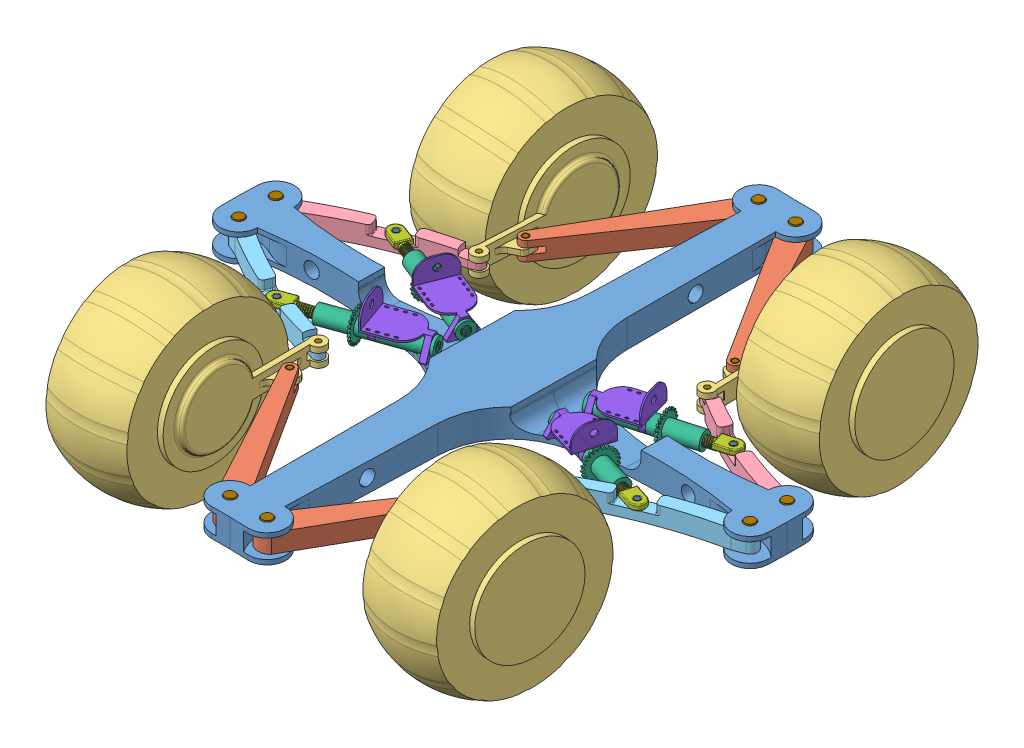
SolidWorks assembly Assembly, configuration Default. Lengths in mm.
Overall size (299.96 98.94 301.96).
45 component instances, 10 part files, 100 mates.
Components (placement in the parent):
- arm new_-1: arm new_ [Default] at (191.3072 172.5892 191.9509) size (299.96 15 300.6)
- arm1-1: arm1 [Default] at (104.0138 167.5892 118.0667) x (0.504061 0 0.863668) z (-0.863668 0 0.504061) size (99.65 10 13.4)
- arm1-2: arm1 [Default] at (58.7662 167.5892 117.3281) x (-0.533042 0 0.846089) z (-0.846089 0 -0.533042) size (99.65 10 13.4)
- arm1-6: arm1 [Default] at (55.0045 177.5892 356.5474) x (-0.50817 0 -0.861257) z (-0.861257 0 0.50817) size (99.65 10 13.4)
- arm1-9: arm1 [Default] at (100.1536 167.5892 357.105) x (0.524834 0 -0.851205) z (0.851205 0 0.524834) size (99.65 10 13.4)
- wheel2-1: wheel2 [Default] at (169.1966 172.6392 141.5765) x (0.999592 0 -0.02857) z (0.02857 0 0.999592) size (79.29 98.57 106.84)
- wheel2-2: wheel2 [Default] at (-7.5959 172.6392 138.9789) x (-0.998723 0 -0.050514) z (-0.050514 0 0.998723) size (79.29 98.57 106.84)
- wheel2-4: wheel2 [Default] at (-10.9833 172.6392 332.7058) x (-0.999915 0 0.013017) z (-0.013017 0 -0.999915) size (79.29 98.57 106.84)
- wheel2-6: wheel2 [Default] at (164.8246 172.6392 336.0802) x (0.996582 0 0.082612) z (0.082612 0 -0.996582) size (79.29 98.57 106.84)
- arm 2 new-1: arm 2 new [Default] at (204.9288 172.5892 223.1767) x (-0.915195 0 -0.403012) z (-0.403012 0 0.915195) size (91 10 10.53)
- arm 2 new-2: arm 2 new [Default] at (-45.319 172.5892 219.268) x (0.926876 0 -0.375368) z (-0.375368 0 -0.926876) size (91 10 10.53)
- arm inverted-1: arm inverted [Default] at (137.6621 167.5892 275.5223) x (0 1 0) z (0.928236 0 -0.371992) size (10 10.53 91)
- arm inverted-2: arm inverted [Default] at (15.309 167.5892 285.0263) x (0 1 0) z (-0.91443 0 -0.404745) size (10 10.53 91)
- pin3new-1: pin3new [Default] at (112.7999 172.5892 230.1102) x (0.109281 -0.915302 0.387659) z (0.248344 0.402768 0.880967) size (16.9 51.81 16.9)
- pin1new-1: pin1new [Default] at (135.513 172.5892 223.7074) x (0 1 0) z (0.271325 0 0.962488) size (5.63 60.02 8)
- pin1new-2: pin1new [Default] at (20.79 172.5892 219.062) x (0 1 0) z (0.369717 0 -0.929144) size (5.63 60.02 8)
- pin1new-4: pin1new [Default] at (19.9082 172.5892 253.6636) x (0 1 0) z (-0.336447 0 -0.941702) size (5.63 60.02 8)
- pin1new-6: pin1new [Default] at (135.3649 172.5892 252.5493) x (0 1 0) z (-0.295537 0 0.955331) size (5.63 60.02 8)
- ring-1: ring [Default] at (115.6874 172.5892 229.2962) x (0 -1 0) z (0.271325 0 0.962488) size (24.27 27.27 20.01)
- ring-2: ring [Default] at (115.4217 172.5892 246.3798) x (0 -1 0) z (-0.295537 0 0.955331) size (24.27 27.27 20.01)
- ring-4: ring [Default] at (43.6955 172.5892 228.1763) x (0 -1 0) z (0.369717 0 -0.929144) size (24.27 27.27 20.01)
- ring-6: ring [Default] at (43.4298 172.5892 245.2599) x (0 -1 0) z (-0.336447 0 -0.941702) size (24.27 27.27 20.01)
- pin3new-2: pin3new [Default] at (112.5557 172.5892 245.4931) x (0.053458 0.983504 -0.172805) z (0.290662 -0.180885 -0.939572) size (16.9 51.81 16.9)
- pin3new-4: pin3new [Default] at (46.483 172.5892 229.2855) x (0.117022 -0.948586 -0.294091) z (0.350709 0.316519 -0.881374) size (16.9 51.81 16.9)
- pin3new-6: pin3new [Default] at (46.2549 172.5892 244.2506) x (-0.303145 -0.433779 -0.848492) z (-0.145944 0.901019 -0.40849) size (16.9 51.81 16.9)
- parallel pin hardened_iso-3: parallel pin hardened_iso [ISO 8734 - 6 x 16 - A - St] at (67.2256 180.5892 377.2599) x (0 -1 0) z (-0.466512 0 0.884515) size (16 6 6)
- parallel pin hardened_iso-4: parallel pin hardened_iso [ISO 8734 - 6 x 16 - A - St] at (87.5318 180.5892 377.5758) x (0 -1 0) z (-0.291462 0 0.956582) size (16 6 6)
- parallel pin hardened_iso-6: parallel pin hardened_iso [ISO 8734 - 6 x 16 - A - St] at (219.2343 180.5892 249.2952) x (0 -1 0) z (-0.078395 0 0.996922) size (16 6 6)
- parallel pin hardened_iso-8: parallel pin hardened_iso [ISO 8734 - 6 x 16 - A - St] at (219.5405 180.5892 229.611) x (0 -1 0) z (0.157499 0 0.987519) size (16 6 6)
- parallel pin hardened_iso-10: parallel pin hardened_iso [ISO 8734 - 6 x 16 - A - St] at (91.8916 180.5892 97.2962) x (0 -1 0) z (0.388757 0 0.92134) size (16 6 6)
- parallel pin hardened_iso-12: parallel pin hardened_iso [ISO 8734 - 6 x 16 - A - St] at (71.5854 180.5892 96.9803) x (0 -1 0) z (0.585753 0 0.810489) size (16 6 6)
- parallel pin hardened_iso-14: parallel pin hardened_iso [ISO 8734 - 6 x 16 - A - St] at (-60.1171 180.5892 225.2609) x (0 -1 0) z (0.730525 0 0.682886) size (16 6 6)
- parallel pin hardened_iso-16: parallel pin hardened_iso [ISO 8734 - 6 x 16 - A - St] at (-60.4233 180.4892 244.9451) x (0 -1 0) z (0.82204 0 0.56943) size (16 6 6)
- groove pin 03_iso-2: groove pin 03_iso [ISO 8741-M3x8-St] at (-17.7449 171.9911 267.1161) x (0 1 0) z (-0.995304 0 0.096799) size (8 3 3)
- groove pin 03_iso-3: groove pin 03_iso [ISO 8741-M3x8-St] at (-16.3609 171.9911 204.2792) x (0 1 0) z (0.188455 0 0.982082) size (8 3 3)
- groove pin 03_iso-5: groove pin 03_iso [ISO 8741-M3x8-St] at (173.9972 171.9911 212.8587) x (0 1 0) z (0.395734 0 0.918365) size (8 3 3)
- groove pin 03_iso-7: groove pin 03_iso [ISO 8741-M3x8-St] at (173.563 171.9911 264.3661) x (0 1 0) z (0.6 0 0.8) size (8 3 3)
- parallel pin hardened_iso-19: parallel pin hardened_iso [ISO 8734 - 3 x 10 - A - St] at (141.2624 177.6392 280.5425) x (0 -1 0) z (0 0 1) size (10 3 3)
- parallel pin hardened_iso-20: parallel pin hardened_iso [ISO 8734 - 3 x 10 - A - St] at (142.6641 177.6392 195.758) x (0 -1 0) z (0.837169 0 0.546944) size (10 3 3)
- parallel pin hardened_iso-22: parallel pin hardened_iso [ISO 8734 - 3 x 10 - A - St] at (17.7405 177.6392 193.73) x (0 -1 0) z (0.395734 0 0.918365) size (10 3 3)
- parallel pin hardened_iso-24: parallel pin hardened_iso [ISO 8734 - 3 x 10 - A - St] at (16.3888 177.6392 278.9436) x (0 -1 0) z (0.837169 0 0.546944) size (10 3 3)
- parallel pin hardened_iso-26: parallel pin hardened_iso [ISO 8734 - 3 x 10 - A - St] at (135.2917 177.5892 300.1161) x (0 -1 0) z (0.837169 0 0.546944) size (10 3 3)
- parallel pin hardened_iso-28: parallel pin hardened_iso [ISO 8734 - 3 x 10 - A - St] at (20.9822 177.5892 298.8855) x (0 -1 0) z (0.837169 0 0.546944) size (10 3 3)
- parallel pin hardened_iso-30: parallel pin hardened_iso [ISO 8734 - 3 x 10 - A - St] at (23.0786 177.5892 173.9744) x (0 -1 0) z (0.6 0 0.8) size (10 3 3)
- parallel pin hardened_iso-32: parallel pin hardened_iso [ISO 8734 - 3 x 10 - A - St] at (137.7611 177.5892 175.89) x (0 -1 0) z (0.773678 0 0.63358) size (10 3 3)
Mates (geometry in assembly coordinates):
- Concentric1: concentric aligned: cylinder of arm new_-1 through (91.8916 180.0892 97.2962) axis (0 -1 0) radius 3; cylinder of arm1-1 through (91.8916 177.5892 97.2962) axis (0 -1 0) radius 3
- Coincident1: coincident anti-aligned: plane of arm new_-1 through (105.3916 177.5892 99.2962) normal (0 -1 0); plane of arm1-1 through (92.5799 177.5892 98.4756) normal (0 1 0)
- Concentric2: concentric aligned: cylinder of arm new_-1 through (71.5854 180.0892 96.9803) axis (0 -1 0) radius 3; cylinder of arm1-2 through (71.5854 177.5892 96.9803) axis (0 -1 0) radius 3
- Coincident2: coincident anti-aligned: plane of arm new_-1 through (58.0297 177.5892 98.5595) normal (0 -1 0); plane of arm1-2 through (70.8575 177.5892 98.1357) normal (0 1 0)
- Concentric5: concentric aligned: circle of arm new_-1; cylinder of arm1-6 through (67.2256 167.5892 377.2599) axis (0 1 0) radius 3
- Concentric7: concentric aligned: cylinder of arm new_-1 through (87.5318 180.0892 377.5758) axis (0 -1 0) radius 3; cylinder of arm1-9 through (87.5318 177.5892 377.5758) axis (0 -1 0) radius 3
- Coincident4: coincident anti-aligned: plane of arm new_-1 through (101.0875 177.5892 375.9966) normal (0 -1 0); plane of arm1-9 through (88.2485 177.5892 376.4134) normal (0 1 0)
- Coincident5: coincident anti-aligned: plane of arm new_-1 through (53.7256 177.5892 375.2599) normal (0 -1 0); plane of arm1-6 through (66.5317 177.5892 376.0838) normal (0 1 0)
- Concentric8: concentric aligned: cylinder of arm1-1 through (137.7611 177.5892 175.89) axis (0 -1 0) radius 1.75; cylinder of wheel2-1 through (137.7611 174.1392 175.89) axis (0 -1 0) radius 1.75
- Coincident6: coincident anti-aligned: plane of arm1-1 through (137.7611 174.1392 175.89) normal (0 -1 0); plane of wheel2-1 through (137.3224 174.1392 177.6712) normal (0 1 0)
- Concentric9: concentric anti-aligned: cylinder of arm1-2 through (23.0786 177.5892 173.9744) axis (0 -1 0) radius 1.75; cylinder of wheel2-2 through (23.0786 171.1392 173.9744) axis (0 1 0) radius 1.75
- Concentric10: concentric anti-aligned: cylinder of arm1-6 through (20.9822 167.5892 298.8855) axis (0 1 0) radius 1.75; cylinder of wheel2-4 through (20.9822 174.1392 298.8855) axis (0 -1 0) radius 1.75
- Coincident8: coincident anti-aligned: plane of arm1-6 through (27.8722 174.1392 294.8202) normal (0 -1 0); plane of wheel2-4 through (21.4485 174.1392 297.1114) normal (0 1 0)
- Concentric11: concentric anti-aligned: cylinder of arm1-9 through (135.2917 177.5892 300.1161) axis (0 -1 0) radius 1.75; cylinder of wheel2-6 through (135.2917 171.1392 300.1161) axis (0 1 0) radius 1.75
- Concentric12: concentric anti-aligned: cylinder of arm new_-1 through (219.5405 180.0892 229.611) axis (0 -1 0) radius 3; cylinder of arm 2 new-1 through (219.5405 167.5892 229.611) axis (0 1 0) radius 3
- Coincident10: coincident anti-aligned: plane of arm new_-1 through (216.5405 177.5892 216.111) normal (0 -1 0); plane of arm 2 new-1 through (204.9288 177.5892 223.1767) normal (0 1 0)
- Concentric13: concentric anti-aligned: cylinder of arm new_-1 through (-60.1171 180.0892 225.2609) axis (0 -1 0) radius 3; cylinder of arm 2 new-2 through (-60.1171 167.5892 225.2609) axis (0 1 0) radius 3
- Coincident11: coincident anti-aligned: plane of arm new_-1 through (-56.6986 177.5892 211.8608) normal (0 -1 0); plane of arm 2 new-2 through (-45.319 177.5892 219.268) normal (0 1 0)
- Concentric14: concentric aligned: cylinder of arm new_-1 through (219.2343 180.0892 249.2952) axis (0 -1 0) radius 3; cylinder of arm inverted-1 through (219.2343 177.5892 249.2952) axis (0 -1 0) radius 3
- Coincident12: coincident anti-aligned: plane of arm new_-1 through (215.8158 177.5892 262.6953) normal (0 -1 0); plane of arm inverted-1 through (219.2343 177.5892 249.2952) normal (0 1 0)
- Concentric15: concentric aligned: cylinder of arm new_-1 through (-60.4233 180.0892 244.9451) axis (0 -1 0) radius 3; cylinder of arm inverted-2 through (-60.4233 177.5892 244.9451) axis (0 -1 0) radius 3
- Coincident13: coincident anti-aligned: plane of arm new_-1 through (-57.4233 177.5892 258.4451) normal (0 -1 0); plane of arm inverted-2 through (-60.4233 177.5892 244.9451) normal (0 1 0)
- Concentric17: concentric aligned: cylinder of wheel2-1 through (142.6641 156.3255 195.758) axis (0 1 0) radius 1.5; cylinder of arm 2 new-1 through (142.6641 167.5892 195.758) axis (0 1 0) radius 1.75
- Concentric18: concentric aligned: cylinder of wheel2-6 through (141.2624 188.9529 280.5425) axis (0 -1 0) radius 1.5; cylinder of arm inverted-1 through (141.2624 177.5892 280.5425) axis (0 -1 0) radius 1.75
- Coincident14: coincident anti-aligned: plane of arm1-9 through (135.2917 174.1392 300.1161) normal (0 -1 0); plane of wheel2-6 through (134.95 174.1392 298.3138) normal (0 1 0)
- Coincident15: coincident anti-aligned: plane of arm1-2 through (23.0786 174.1392 173.9744) normal (0 -1 0); plane of wheel2-2 through (23.478 174.1392 175.7648) normal (0 1 0)
- Concentric19: concentric anti-aligned: cylinder of wheel2-2 through (17.7405 188.9529 193.73) axis (0 -1 0) radius 1.5; cylinder of arm 2 new-2 through (17.7405 167.5892 193.73) axis (0 1 0) radius 1.75
- Concentric20: concentric anti-aligned: cylinder of wheel2-4 through (16.3888 156.3255 278.9436) axis (0 1 0) radius 1.5; cylinder of arm inverted-2 through (16.3888 177.5892 278.9436) axis (0 -1 0) radius 1.75
- Concentric21: concentric anti-aligned: cylinder of arm 2 new-1 through (173.9972 177.5892 212.8587) axis (0 -1 0) radius 1.5; cylinder of pin1new-1 through (173.9972 172.5892 212.8587) axis (0 1 0) radius 1.5
- Coincident16: coincident anti-aligned: plane of arm 2 new-1 through (185.0642 172.5892 210.0586) normal (0 1 0); plane of pin1new-1 through (135.513 172.5892 223.7074) normal (0 -1 0)
- Concentric22: concentric anti-aligned: cylinder of arm 2 new-2 through (-16.3609 177.5892 204.2792) axis (0 -1 0) radius 1.5; cylinder of pin1new-2 through (-16.3609 172.5892 204.2792) axis (0 1 0) radius 1.5
- Coincident17: coincident anti-aligned: plane of arm 2 new-2 through (-22.0667 172.5892 214.1668) normal (0 1 0); plane of pin1new-2 through (20.79 172.5892 219.062) normal (0 -1 0)
- Concentric23: concentric aligned: cylinder of arm inverted-2 through (-17.7449 167.5892 267.1161) axis (0 1 0) radius 1.5; cylinder of pin1new-4 through (-17.7449 172.5892 267.1161) axis (0 1 0) radius 1.5
- Coincident18: coincident anti-aligned: plane of arm inverted-2 through (-10.9426 172.5892 273.9841) normal (0 1 0); plane of pin1new-4 through (19.9082 172.5892 253.6636) normal (0 -1 0)
- Concentric24: concentric aligned: cylinder of arm inverted-1 through (173.563 167.5892 264.3661) axis (0 1 0) radius 1.5; cylinder of pin1new-6 through (173.563 172.5892 264.3661) axis (0 1 0) radius 1.5
- Coincident19: coincident anti-aligned: plane of arm inverted-1 through (163.8968 172.5892 264.44) normal (0 1 0); plane of pin1new-6 through (135.3649 172.5892 252.5493) normal (0 -1 0)
- Concentric25: concentric anti-aligned: cylinder of arm new_-1 through (115.6874 165.0892 229.2962) axis (0 1 0) radius 1.5; cylinder of ring-1 through (115.6874 177.0902 229.2962) axis (0 -1 0) radius 1.5
- Coincident20: coincident anti-aligned: plane of arm new_-1 through (156.8916 168.0892 239.611) normal (0 1 0); plane of ring-1 through (137.6248 168.0892 231.5126) normal (0 -1 0)
- Concentric26: concentric anti-aligned: cylinder of arm new_-1 through (115.4217 165.0892 246.3798) axis (0 1 0) radius 1.5; cylinder of ring-2 through (115.4217 177.0902 246.3798) axis (0 -1 0) radius 1.5
- Coincident21: coincident anti-aligned: plane of arm new_-1 through (156.8916 168.0892 239.611) normal (0 1 0); plane of ring-2 through (132.6289 168.0892 260.1664) normal (0 -1 0)
- Concentric27: concentric anti-aligned: cylinder of arm new_-1 through (43.6955 165.0892 228.1763) axis (0 1 0) radius 1.5; cylinder of ring-4 through (43.6955 177.0902 228.1763) axis (0 -1 0) radius 1.5
- Coincident22: coincident anti-aligned: plane of arm new_-1 through (2.1905 168.0892 237.2046) normal (0 1 0); plane of ring-4 through (27.6252 168.0892 213.0797) normal (0 -1 0)
- Concentric28: concentric anti-aligned: cylinder of arm new_-1 through (43.4298 165.0892 245.2599) axis (0 1 0) radius 1.5; cylinder of ring-6 through (43.4298 177.0902 245.2599) axis (0 -1 0) radius 1.5
- Coincident23: coincident anti-aligned: plane of arm new_-1 through (2.1905 168.0892 237.2046) normal (0 1 0); plane of ring-6 through (21.3922 168.0892 244.5474) normal (0 -1 0)
- Coincident24: coincident anti-aligned: plane of pin3new-1 through (113.1261 170.7767 225.7388) normal (0.962488 0 -0.271325); plane of ring-1 through (114.2437 172.5892 229.7032) normal (-0.962488 0 0.271325)
- Concentric29: concentric aligned: cylinder of pin3new-1 through (161.8868 172.5892 216.2726) axis (-0.962488 0 0.271325) radius 4.5; cylinder of ring-1 through (117.1311 172.5892 228.8892) axis (-0.962488 0 0.271325) radius 4
- Coincident25: coincident anti-aligned: plane of ring-2 through (113.9887 172.5892 245.9365) normal (-0.955331 0 -0.295537); plane of pin3new-2 through (112.6807 173.4032 250.1645) normal (0.955331 0 0.295537)
- Concentric30: concentric aligned: cylinder of ring-2 through (116.8547 172.5892 246.8231) axis (-0.955331 0 -0.295537) radius 4; cylinder of pin3new-2 through (161.2776 172.5892 260.5655) axis (-0.955331 0 -0.295537) radius 4.5
- Coincident26: coincident anti-aligned: plane of ring-4 through (45.0893 172.5892 228.7309) normal (0.929144 0 0.369717); plane of pin3new-4 through (43.5111 171.1649 232.6971) normal (-0.929144 0 -0.369717)
- Concentric31: concentric aligned: cylinder of ring-4 through (42.3018 172.5892 227.6218) axis (0.929144 0 0.369717) radius 4; cylinder of pin3new-4 through (-0.9034 172.5892 210.4299) axis (0.929144 0 0.369717) radius 4.5
- Coincident27: coincident anti-aligned: plane of ring-6 through (44.8424 172.5892 244.7552) normal (0.941702 0 -0.336447); plane of pin3new-6 through (45.4991 168.5346 246.5934) normal (-0.941702 0 0.336447)
- Concentric32: concentric aligned: cylinder of ring-6 through (42.0173 172.5892 245.7646) axis (0.941702 0 -0.336447) radius 4; cylinder of pin3new-6 through (-1.7719 172.5892 261.4094) axis (0.941702 0 -0.336447) radius 4.5
- Screw1: screw = 1 anti-aligned: cylinder of pin3new-1 through (161.8868 172.5892 216.2726) axis (-0.962488 0 0.271325) radius 2.5; cylinder of pin1new-1 through (121.0757 172.5892 227.7772) axis (0.962488 0 -0.271325) radius 2.5
- Screw2: screw = 1 anti-aligned: cylinder of pin1new-2 through (34.7272 172.5892 224.6077) axis (-0.929144 0 -0.369717) radius 2.5; cylinder of pin3new-4 through (-0.9034 172.5892 210.4299) axis (0.929144 0 0.369717) radius 2.5
- Screw4: screw = 1 anti-aligned: cylinder of pin1new-4 through (34.0337 172.5892 248.6169) axis (-0.941702 0 0.336447) radius 2.5; cylinder of pin3new-6 through (-1.7719 172.5892 261.4094) axis (0.941702 0 -0.336447) radius 2.5
- Screw5: screw = 1 anti-aligned: cylinder of pin1new-6 through (121.035 172.5892 248.1163) axis (0.955331 0 0.295537) radius 2.5; cylinder of pin3new-2 through (161.2776 172.5892 260.5655) axis (-0.955331 0 -0.295537) radius 2.5
- LimitDistance1: limit distance = 9.1363 mm anti-aligned: plane of pin1new-2 through (-7.9135 172.5892 203.3355) normal (0.929144 0 0.369717); plane of pin3new-4 through (-0.9034 172.5892 210.4299) normal (-0.929144 0 -0.369717)
- LimitDistance2: limit distance = 5.0824 mm anti-aligned: plane of pin1new-1 through (167.8638 172.5892 218.7436) normal (-0.962488 0 0.271325); plane of pin3new-1 through (161.8868 172.5892 216.2726) normal (0.962488 0 -0.271325)
- LimitDistance3: limit distance = 5.3598 mm anti-aligned: plane of pin3new-2 through (161.2776 172.5892 260.5655) normal (0.955331 0 0.295537); plane of pin1new-6 through (165.2158 172.5892 265.9709) normal (-0.955331 0 -0.295537)
- LimitDistance4: limit distance = 9.4618 mm anti-aligned: plane of pin3new-6 through (-1.7719 172.5892 261.4094) normal (-0.941702 0 0.336447); plane of pin1new-4 through (-12.0279 172.5892 260.8259) normal (0.941702 0 -0.336447)
- Concentric37: concentric anti-aligned: cylinder of arm new_-1 through (67.2256 180.0892 377.2599) axis (0 -1 0) radius 3; cylinder of parallel pin hardened_iso-3 through (67.2256 186.9392 377.2599) axis (0 1 0) radius 3
- Distance5: distance = 0.5 mm aligned: plane of parallel pin hardened_iso-3 through (69.5947 180.5892 378.5094) normal (0 1 0); plane of arm new_-1 through (91.8916 180.0892 97.2962) normal (0 1 0)
- Concentric38: concentric anti-aligned: cylinder of arm new_-1 through (87.5318 180.0892 377.5758) axis (0 -1 0) radius 3; cylinder of parallel pin hardened_iso-4 through (87.5318 186.9392 377.5758) axis (0 1 0) radius 3
- Distance6: distance = 0.5 mm aligned: plane of parallel pin hardened_iso-4 through (90.094 180.5892 378.3564) normal (0 1 0); plane of arm new_-1 through (91.8916 180.0892 97.2962) normal (0 1 0)
- Concentric39: concentric anti-aligned: cylinder of arm inverted-1 through (219.2343 177.5892 249.2952) axis (0 -1 0) radius 3; cylinder of parallel pin hardened_iso-6 through (219.2343 186.9392 249.2952) axis (0 1 0) radius 3
- Distance7: distance = 0.5 mm aligned: plane of parallel pin hardened_iso-6 through (221.9045 180.5892 249.5052) normal (0 1 0); plane of arm new_-1 through (91.8916 180.0892 97.2962) normal (0 1 0)
- Concentric40: concentric anti-aligned: cylinder of arm new_-1 through (219.5405 180.0892 229.611) axis (0 -1 0) radius 3; cylinder of parallel pin hardened_iso-8 through (219.5405 186.9392 229.611) axis (0 1 0) radius 3
- Distance8: distance = 0.5 mm aligned: plane of parallel pin hardened_iso-8 through (222.1855 180.5892 229.1892) normal (0 1 0); plane of arm new_-1 through (91.8916 180.0892 97.2962) normal (0 1 0)
- Concentric41: concentric anti-aligned: cylinder of arm new_-1 through (91.8916 180.0892 97.2962) axis (0 -1 0) radius 3; cylinder of parallel pin hardened_iso-10 through (91.8916 186.9392 97.2962) axis (0 1 0) radius 3
- Distance9: distance = 0.5 mm aligned: plane of parallel pin hardened_iso-10 through (94.3594 180.5892 96.2549) normal (0 1 0); plane of arm new_-1 through (91.8916 180.0892 97.2962) normal (0 1 0)
- Concentric42: concentric anti-aligned: cylinder of arm new_-1 through (71.5854 180.0892 96.9803) axis (0 -1 0) radius 3; cylinder of parallel pin hardened_iso-12 through (71.5854 186.9392 96.9803) axis (0 1 0) radius 3
- Distance10: distance = 0.5 mm aligned: plane of parallel pin hardened_iso-12 through (73.7563 180.5892 95.4114) normal (0 1 0); plane of arm new_-1 through (91.8916 180.0892 97.2962) normal (0 1 0)
- Concentric43: concentric anti-aligned: cylinder of arm new_-1 through (-60.1171 180.0892 225.2609) axis (0 -1 0) radius 3; cylinder of parallel pin hardened_iso-14 through (-60.1171 186.9392 225.2609) axis (0 1 0) radius 3
- Distance12: distance = 0.5 mm aligned: plane of parallel pin hardened_iso-14 through (-58.288 180.5892 223.3042) normal (0 1 0); plane of arm new_-1 through (71.5854 180.0892 96.9803) normal (0 1 0)
- Concentric44: concentric anti-aligned: cylinder of arm new_-1 through (-60.4233 180.0892 244.9451) axis (0 -1 0) radius 3; cylinder of parallel pin hardened_iso-16 through (-60.4233 186.8392 244.9451) axis (0 1 0) radius 3
- Distance13: distance = 0.4 mm aligned: plane of parallel pin hardened_iso-16 through (-58.8981 180.4892 242.7433) normal (0 1 0); plane of arm new_-1 through (71.5854 180.0892 96.9803) normal (0 1 0)
- Concentric45: concentric anti-aligned: cylinder of arm inverted-2 through (-17.7449 167.5892 267.1161) axis (0 1 0) radius 1.5; cylinder of groove pin 03_iso-2 through (-17.7449 114.9911 267.1161) axis (0 -1 0) radius 1.5
- Coincident31: coincident anti-aligned: plane of pin1new-4 through (19.9082 175.5892 253.6636) normal (0 1 0); circle of groove pin 03_iso-2
- Concentric46: concentric anti-aligned: cylinder of pin1new-2 through (-16.3609 172.5892 204.2792) axis (0 1 0) radius 1.5; cylinder of groove pin 03_iso-3 through (-16.3609 114.9911 204.2792) axis (0 -1 0) radius 1.5
- Coincident32: coincident anti-aligned: plane of pin1new-2 through (20.79 175.5892 219.062) normal (0 1 0); circle of groove pin 03_iso-3
- Concentric47: concentric anti-aligned: cylinder of pin1new-1 through (173.9972 172.5892 212.8587) axis (0 1 0) radius 1.5; cylinder of groove pin 03_iso-5 through (173.9972 114.9911 212.8587) axis (0 -1 0) radius 1.5
- Coincident33: coincident anti-aligned: plane of pin1new-1 through (135.513 175.5892 223.7074) normal (0 1 0); circle of groove pin 03_iso-5
- Concentric48: concentric anti-aligned: cylinder of pin1new-6 through (173.563 172.5892 264.3661) axis (0 1 0) radius 1.5; cylinder of groove pin 03_iso-7 through (173.563 114.9911 264.3661) axis (0 -1 0) radius 1.5
- Coincident34: coincident anti-aligned: plane of pin1new-6 through (135.3649 175.5892 252.5493) normal (0 1 0); circle of groove pin 03_iso-7
- Concentric49: concentric anti-aligned: cylinder of wheel2-6 through (141.2624 188.9529 280.5425) axis (0 -1 0) radius 1.5; cylinder of parallel pin hardened_iso-19 through (141.2624 183.9892 280.5425) axis (0 1 0) radius 1.5
- Coincident35: coincident aligned: plane of wheel2-6 through (137.5152 177.6392 333.8164) normal (0 1 0); plane of parallel pin hardened_iso-19 through (142.6285 177.6392 280.5425) normal (0 1 0)
- Concentric50: concentric aligned: circle of wheel2-1; cylinder of parallel pin hardened_iso-20 through (142.6641 183.9892 195.758) axis (0 1 0) radius 1.5
- Coincident37: coincident aligned: plane of wheel2-1 through (141.8048 177.6392 142.3594) normal (0 1 0); plane of parallel pin hardened_iso-20 through (143.4112 177.6392 194.6144) normal (0 1 0)
- Concentric51: concentric anti-aligned: cylinder of wheel2-2 through (17.7405 188.9529 193.73) axis (0 -1 0) radius 1.5; cylinder of parallel pin hardened_iso-22 through (17.7405 183.9892 193.73) axis (0 1 0) radius 1.5
- Coincident38: coincident aligned: plane of wheel2-2 through (19.7722 177.6392 140.3631) normal (0 1 0); plane of parallel pin hardened_iso-22 through (18.995 177.6392 193.1894) normal (0 1 0)
- Concentric52: concentric aligned: cylinder of wheel2-4 through (16.3888 156.3255 278.9436) axis (0 1 0) radius 1.5; cylinder of parallel pin hardened_iso-24 through (16.3888 183.9892 278.9436) axis (0 1 0) radius 1.5
- Coincident39: coincident aligned: plane of wheel2-4 through (16.4174 177.6392 332.3491) normal (0 1 0); plane of parallel pin hardened_iso-24 through (17.136 177.6392 277.8) normal (0 1 0)
- Concentric53: concentric aligned: circle of arm1-9; cylinder of parallel pin hardened_iso-26 through (135.2917 183.9392 300.1161) axis (0 1 0) radius 1.5
- Coincident40: coincident aligned: plane of arm1-9 through (88.2485 177.5892 376.4134) normal (0 1 0); plane of parallel pin hardened_iso-26 through (136.0388 177.5892 298.9725) normal (0 1 0)
- Concentric54: concentric aligned: cylinder of arm1-6 through (20.9822 167.5892 298.8855) axis (0 1 0) radius 1.75; cylinder of parallel pin hardened_iso-28 through (20.9822 183.9392 298.8855) axis (0 1 0) radius 1.5
- Coincident41: coincident aligned: plane of arm1-6 through (66.5317 177.5892 376.0838) normal (0 1 0); plane of parallel pin hardened_iso-28 through (21.7293 177.5892 297.7419) normal (0 1 0)
- Concentric55: concentric anti-aligned: cylinder of arm1-2 through (23.0786 177.5892 173.9744) axis (0 -1 0) radius 1.75; cylinder of parallel pin hardened_iso-30 through (23.0786 183.9392 173.9744) axis (0 1 0) radius 1.5
- Coincident42: coincident aligned: plane of arm1-2 through (70.8575 177.5892 98.1357) normal (0 1 0); plane of parallel pin hardened_iso-30 through (24.1714 177.5892 173.1548) normal (0 1 0)
- Concentric56: concentric anti-aligned: cylinder of arm1-1 through (137.7611 177.5892 175.89) axis (0 -1 0) radius 1.75; cylinder of parallel pin hardened_iso-32 through (137.7611 183.9392 175.89) axis (0 1 0) radius 1.5
- Coincident43: coincident aligned: plane of arm1-1 through (92.5799 177.5892 98.4756) normal (0 1 0); plane of parallel pin hardened_iso-32 through (138.6266 177.5892 174.8331) normal (0 1 0)
